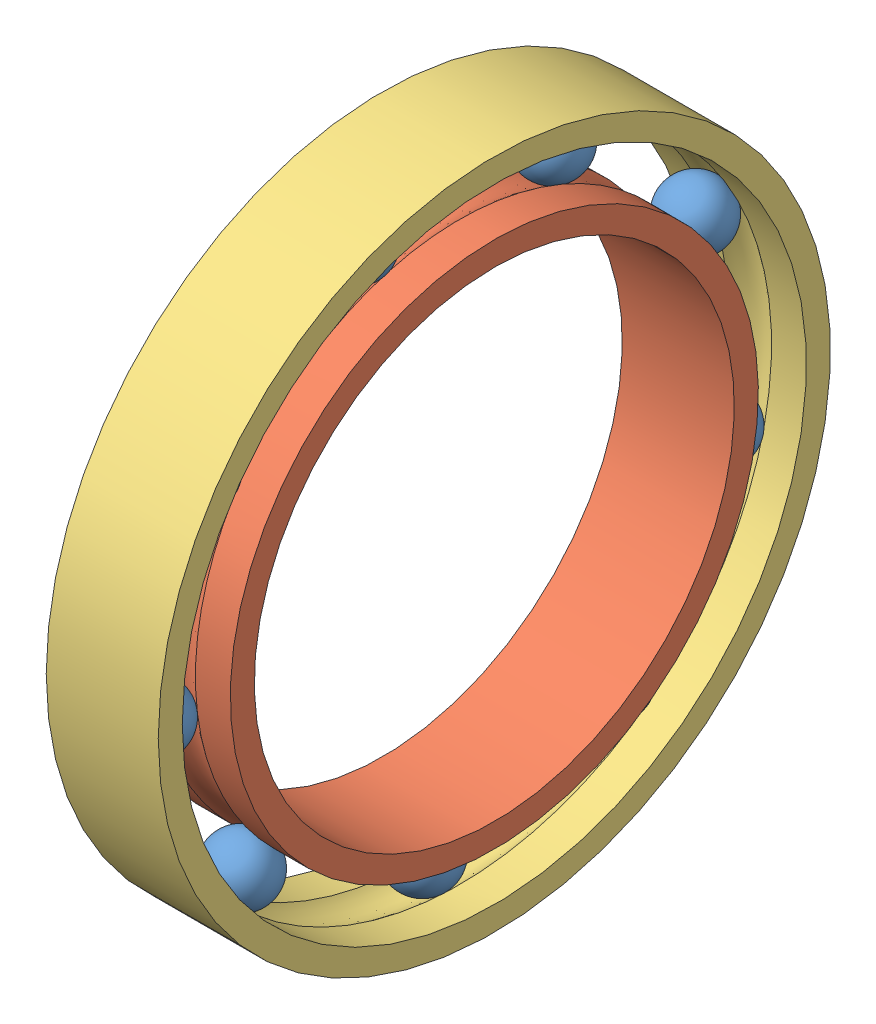
SolidWorks assembly 轴承(D42d30B7), configuration 默认. Lengths in mm.
Overall size (7 42 42).
11 component instances, 3 part files, 3 mates.
Components (placement in the parent):
- 轴承内球(D42d30B7)-1: 轴承内球(D42d30B7) [默认] at (-19.7279 -11.8633 3.0614) x (0.999552 0.02502 0.016415) z (-0.019896 0.145902 0.989099) size (4 4 4)
- 轴承内圈(D42d30B7)-1: 轴承内圈(D42d30B7) [默认] at (-19.7279 -16.4134 -5.8636) x (1 0 0) z (0 -0.982104 0.188342) size (7 33 33)
- 轴承外圈(D42d30B7)-1: 轴承外圈(D42d30B7) [默认] at (-19.7279 1.2645 8.7463) size (7 42 42)
- 轴承内球(D42d30B7)-10: 轴承内球(D42d30B7) [默认] at (-19.7279 -0.876 8.6186) x (0.999552 0.029718 -0.003508) z (-0.019896 0.747548 0.66391) size (4 4 4)
- 轴承内球(D42d30B7)-11: 轴承内球(D42d30B7) [默认] at (-19.7279 11.1129 5.8131) x (0.999552 0.02051 -0.02179) z (-0.019896 0.999408 0.02807) size (4 4 4)
- 轴承内球(D42d30B7)-12: 轴承内球(D42d30B7) [默认] at (-19.7279 18.4935 -4.0423) x (0.999552 0.001706 -0.029876) z (-0.019896 0.783634 -0.620904) size (4 4 4)
- 轴承内球(D42d30B7)-13: 轴承内球(D42d30B7) [默认] at (-19.7279 17.8125 -16.3362) x (0.999552 -0.017897 -0.023983) z (-0.019896 0.201189 -0.97935) size (4 4 4)
- 轴承内球(D42d30B7)-14: 轴承内球(D42d30B7) [默认] at (-19.7279 9.3885 -25.3161) x (0.999552 -0.029126 -0.006868) z (-0.019896 -0.475395 -0.879548) size (4 4 4)
- 轴承内球(D42d30B7)-15: 轴承内球(D42d30B7) [默认] at (-19.7279 -2.8369 -26.7802) x (0.999552 -0.026726 0.013461) z (-0.019896 -0.929536 -0.368195) size (4 4 4)
- 轴承内球(D42d30B7)-16: 轴承内球(D42d30B7) [默认] at (-19.7279 -13.1432 -20.0435) x (0.999552 -0.011821 0.027491) z (-0.019896 -0.948737 0.31544) size (4 4 4)
- 轴承内球(D42d30B7)-17: 轴承内球(D42d30B7) [默认] at (-19.7279 -16.708 -8.2581) x (0.999552 0.008615 0.028657) z (-0.019896 -0.524013 0.851478) size (4 4 4)
Mates (geometry in assembly coordinates):
- 重合1: coincident: plane of 轴承内圈(D42d30B7)-1 through (-23.2279 -13.4671 -6.4286) normal (-1 0 0); plane of 轴承外圈(D42d30B7)-1 through (-23.2279 1.2645 10.2463) normal (-1 0 0)
- 同心1: concentric: circle of 轴承内圈(D42d30B7)-1; circle of 轴承外圈(D42d30B7)-1
- 相切2: tangent: sphere of 轴承内球(D42d30B7)-1; torus of 轴承内圈(D42d30B7)-1
